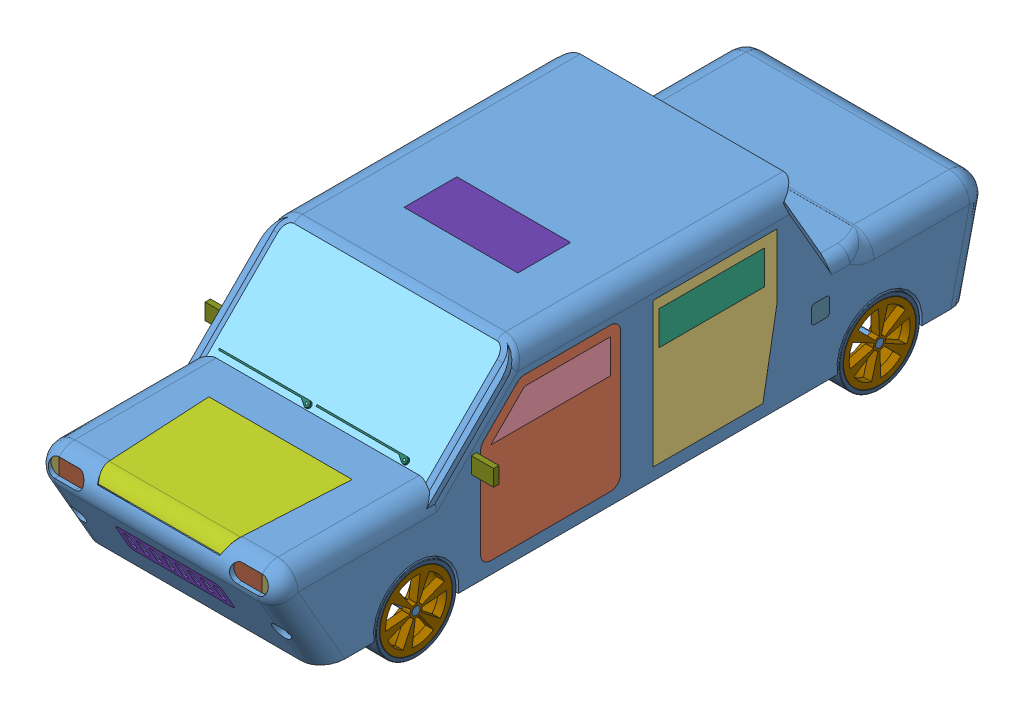
SolidWorks assembly Car Assembly, configuration Default. Lengths in mm.
Overall size (710 598.98 1752.8).
32 component instances, 17 part files, 91 mates.
Components (placement in the parent):
- Car Body-1: Car Body [Default] at origin size (608.06 474.25 1752.8)
- Car Door-4: Car Door [Default] at (-297 0 0) x (0 0 -1) z (1 0 0) size (344.71 355 3)
- Car Door-5: Car Door [Default] at (300 0 0) x (0 0 -1) z (1 0 0) size (344.71 355 3)
- Back Door-1: Back Door [Default] at (300 0 0) x (0 0 -1) z (1 0 0) size (304.4 355 3)
- Back Door-2: Back Door [Default] at (-297 0 0) x (0 0 -1) z (1 0 0) size (304.4 355 3)
- Front Door Window-3: Front Door Window [Default] at (300 0 0) x (0 0 -1) z (1 0 0) size (294.71 83.19 3)
- Front Door Window-4: Front Door Window [Default] at (-297 0 0) x (0 0 -1) z (1 0 0) size (294.71 83.19 3)
- Windshield-1: Windshield [Default] at (0 -20.2625 -20.3999) x (1 0 0) z (0 0.707107 0.707107) size (540 276.32 9)
- Back Door Window-1: Back Door Window [Default] at (300 0 0) x (0 0 -1) z (1 0 0) size (259.4 83.19 3)
- Back Door Window-2: Back Door Window [Default] at (-297 0 0) x (0 0 -1) z (1 0 0) size (259.4 83.19 3)
- Hood-3: Hood [Default] at (0 0 101.0363) size (352.8 60.9 300)
- Grill-1: Grill [Default] x (1 0 0) z (0 -0.5 0.866025) size (260 80.83 3)
- Rim-2: Rim [Default] at (210 -65.3854 -451.6615) x (0 0.28359 0.958946) z (-1 0 0) size (178 178 90)
- TIre Rubber-2: TIre Rubber [Default] at (300 157.4707 -48.093) x (0 -0.660547 -0.750784) z (1 0 0) size (198 198 90)
- Rim-3: Rim [Default] at (210 -204.7414 -1451.8024) x (0 0.918717 0.394916) z (-1 0 0) size (178 178 90)
- TIre Rubber-3: TIre Rubber [Default] at (300 222.8939 -1267.9808) x (0 -0.918717 -0.394916) z (1 0 0) size (198 198 90)
- Rim-4: Rim [Default] at (-210 37.9993 -0.654) x (0 -0.162417 -0.986722) z (1 0 0) size (178 178 90)
- TIre Rubber-4: TIre Rubber [Default] at (-300 -37.6009 -459.9436) x (0 0.162417 0.986722) z (-1 0 0) size (198 198 90)
- Rim-5: Rim [Default] at (-210 197.2827 -1228.1952) x (0 -0.8201 -0.57222) z (1 0 0) size (178 178 90)
- TIre Rubber-5: TIre Rubber [Default] at (-300 -184.4493 -1494.5465) x (0 0.8201 0.57222) z (-1 0 0) size (198 198 90)
- Headlight-2: Headlight [Default] at (0 0 96.0363) size (70 40 25)
- Headlight-3: Headlight [Default] at (0 0 71.0363) x (-1 0 0) z (0 0 -1) size (70 40 25)
- Indicator-2: Indicator [Default] at (0 0 96.0363) size (20 40 25)
- Indicator-3: Indicator [Default] at (0 0 71.0363) x (-1 0 0) z (0 0 -1) size (20 40 25)
- Fog Light-2: Fog Light [Default] at (-16.163 -36.9046 1.0363) x (0.988432 -0.151667 0) z (0 0 1) size (40 40 25)
- Fog Light-3: Fog Light [Default] at (452.9059 257.7511 1.0363) x (0.51071 0.859753 0) z (0 0 1) size (40 40 25)
- Fuel Tank Lid-2: Fuel Tank Lid [Default] at (300 0 0) x (0 0 -1) z (1 0 0) size (45 45 3)
- Wiper-2: Wiper [Default] at (0 -20.3312 -20.3312) x (1 0 0) z (0 0.707107 0.707107) size (227.5 15 6)
- Wiper-3: Wiper [Default] at (-240 -20.3312 -20.3312) x (1 0 0) z (0 0.707107 0.707107) size (227.5 15 6)
- Driver Mirror-1: Driver Mirror [Default] at (300 0 0) x (0 0 -1) z (1 0 0) size (13 40 55)
- Driver Mirror-2: Driver Mirror [Default] at (-355 0 0) x (0 0 -1) z (1 0 0) size (13 40 55)
- Sun Roof-2: Sun Roof [Default] at (0 450 0) x (1 0 0) z (0 1 0) size (280 130 3)
Mates (geometry in assembly coordinates):
- Coincident17: coincident aligned: line of Car Body-1 through (-300 276.8092 -391.4665) axis (0 -1 0); line of Car Door-4 through (-300 276.8092 -391.4665) axis (0 -1 0)
- Coincident18: coincident anti-aligned: plane of Car Body-1 through (-290 385 -711.1767) normal (0 -1 0); plane of Car Door-4 through (-300 385 -711.1767) normal (0 1 0)
- LimitAngle1: limit planar angle = 0 rad aligned: line of Car Door-4 through (-300 385 -711.1767) axis (0 0 1); line of Car Body-1 through (-300 385 -711.1767) axis (0 0 1)
- Coincident20: coincident aligned: line of Car Body-1 through (300 276.8092 -391.4665) axis (0 -1 0); line of Car Door-5 through (300 276.8092 -391.4665) axis (0 -1 0)
- Coincident21: coincident anti-aligned: plane of Car Body-1 through (290 385 -711.1767) normal (0 -1 0); plane of Car Door-5 through (297 385 -711.1767) normal (0 1 0)
- LimitAngle2: limit planar angle = 0 rad aligned: line of Car Door-5 through (300 385 -711.1767) axis (0 0 1); line of Car Body-1 through (300 385 -711.1767) axis (0 0 1)
- InPlace4: in place: plane of Car Body-1 through (300 0 0) normal (1 0 0); plane of ? through (300 0 0) normal (1 0 0); moOrthogonalPlaneRef_w of Car Body-1 through (300 0 0) normal (1 0 0); plane of ? through (300 0 0) normal (0 1 0); plane of Car Body-1 through (300 0 0) normal (1 0 0); plane of ? through (300 0 0) normal (0 0 -1); plane of Car Body-1 through (300 0 0) normal (1 0 0); unknown of ?
- Coincident23: coincident aligned: plane of Car Body-1; plane of Back Door-1
- Coincident24: coincident aligned: moOrthogonalPlaneRef_w of Car Body-1 through (300 0 0) normal (0 1 0); plane of Part8^Car Assembly-1 through (300 0 0) normal (0 1 0)
- Coincident25: coincident anti-aligned: moOrthogonalPlaneRef_w of Car Body-1 through (300 0 0) normal (0 0 1); plane of Part8^Car Assembly-1 through (300 0 0) normal (0 0 -1)
- Coincident26: coincident anti-aligned: plane of Car Body-1 through (-290 385 -816.1767) normal (0 0 -1); plane of Back Door-2 through (-300 385 -816.1767) normal (0 0 1)
- Coincident27: coincident anti-aligned: plane of Car Body-1 through (-290 30 -816.1767) normal (0 1 0); plane of Back Door-2 through (-300 30 -816.1767) normal (0 -1 0)
- Coincident28: coincident aligned: plane of Car Body-1 through (-300 0 0) normal (-1 0 0); plane of Back Door-2 through (-300 0 0) normal (-1 0 0)
- InPlace5: in place: plane of ? through (300 55 -711.1767) normal (1 0 0); plane of ? through (300 0 0) normal (1 0 0); plane of ? through (300 55 -711.1767) normal (1 0 0); plane of ? through (300 0 0) normal (0 1 0); plane of ? through (300 55 -711.1767) normal (1 0 0); plane of ? through (300 0 0) normal (0 0 -1); plane of ? through (300 55 -711.1767) normal (1 0 0); unknown of ?
- Coincident29: coincident aligned: plane of Car Door-5; plane of Front Door Window-3
- Coincident30: coincident aligned: moOrthogonalPlaneRef_w of Car Door-5 through (300 0 0) normal (0 1 0); plane of Part9^Car Assembly-1 through (300 0 0) normal (0 1 0)
- Coincident31: coincident anti-aligned: moOrthogonalPlaneRef_w of Car Door-5 through (300 0 0) normal (0 0 1); plane of Part9^Car Assembly-1 through (300 0 0) normal (0 0 -1)
- Coincident32: coincident anti-aligned: plane of Car Door-4 through (-300 276.8092 -416.4665) normal (0 -0.707107 -0.707107); plane of Front Door Window-4 through (-300 360 -499.6574) normal (0 0.707107 0.707107)
- Coincident33: coincident anti-aligned: plane of Car Door-4 through (-300 276.8092 -711.1767) normal (0 1 0); plane of Front Door Window-4 through (-300 276.8092 -416.4665) normal (0 -1 0)
- Coincident34: coincident aligned: plane of Car Door-4 through (-300 55 -711.1767) normal (-1 0 0); plane of Front Door Window-4 through (-300 0 0) normal (-1 0 0)
- InPlace8: in place: plane of ? through (300 0 0) normal (1 0 0); plane of ? through (300 0 0) normal (1 0 0); plane of ? through (300 0 0) normal (1 0 0); plane of ? through (300 0 0) normal (0 1 0); plane of ? through (300 0 0) normal (1 0 0); plane of ? through (300 0 0) normal (0 0 -1); plane of ? through (300 0 0) normal (1 0 0); unknown of ?
- Coincident41: coincident aligned: plane of Back Door-1; plane of Back Door Window-1
- Coincident42: coincident aligned: moOrthogonalPlaneRef_w of Back Door-1 through (300 0 0) normal (0 1 0); plane of Part12^Car Assembly-1 through (300 0 0) normal (0 1 0)
- Coincident43: coincident anti-aligned: moOrthogonalPlaneRef_w of Back Door-1 through (300 0 0) normal (0 0 1); plane of Part12^Car Assembly-1 through (300 0 0) normal (0 0 -1)
- Coincident44: coincident anti-aligned: plane of Back Door-2 through (-300 276.8092 -831.1767) normal (0 0 -1); plane of Back Door Window-2 through (-300 360 -831.1767) normal (0 0 1)
- Coincident45: coincident anti-aligned: plane of Back Door-2 through (-300 360 -831.1767) normal (0 -1 0); plane of Back Door Window-2 through (-300 360 -1090.5748) normal (0 1 0)
- Coincident46: coincident aligned: plane of Back Door-2 through (-300 0 0) normal (-1 0 0); plane of Back Door Window-2 through (-300 0 0) normal (-1 0 0)
- Coincident57: coincident aligned: line of Car Body-1 through (176.3977 250 -198.9637) axis (-1 0 0); line of Hood-3 through (176.3977 250 -198.9637) axis (-1 0 0)
- Coincident58: coincident: point of Car Body-1; point of Hood-3
- LimitAngle4: limit planar angle = 0 rad aligned: plane of Hood-3 through (0 250 101.0363) normal (0 1 0); plane of Car Body-1 through (300 250 -290.6624) normal (0 1 0)
- InPlace11: in place: plane of Grill-1 through (0 0 0) normal (0 -0.5 0.866025); plane of Grill-1 through (0 0 0) normal (0 0.866025 0.5); plane of Grill-1 through (0 0 0) normal (1 0 0); unknown of Grill-1
- Coincident60: coincident aligned: 
- Coincident61: coincident aligned: plane of Part15^Car Assembly-1 through (0 0 0) normal (0 0.866025 0.5)
- Coincident62: coincident anti-aligned: plane of Part15^Car Assembly-1 through (0 0 0) normal (1 0 0)
- Concentric1: concentric anti-aligned: cylinder of Car Body-1 through (300 15 -232.735) axis (-1 0 0) radius 10; cylinder of Rim-2 through (210 15 -232.735) axis (1 0 0) radius 10
- Coincident69: coincident aligned: plane of Car Body-1 through (300 0 0) normal (1 0 0); plane of Rim-2 through (300 15 -232.735) normal (1 0 0)
- Concentric2: concentric anti-aligned: cylinder of Rim-2 through (300 15 -232.735) axis (-1 0 0) radius 89; cylinder of TIre Rubber-2 through (210 15 -232.735) axis (1 0 0) radius 89
- Coincident70: coincident aligned: plane of Rim-2 through (300 15 -232.735) normal (1 0 0); plane of TIre Rubber-2 through (300 15 -232.735) normal (1 0 0)
- Lock1: lock: unknown of Rim-2; unknown of TIre Rubber-2
- Concentric3: concentric anti-aligned: cylinder of Car Body-1 through (300 15 -1373.6723) axis (-1 0 0) radius 10; cylinder of Rim-3 through (210 15 -1373.6723) axis (1 0 0) radius 10
- Coincident72: coincident aligned: plane of Car Body-1 through (300 15 -1373.6723) normal (1 0 0); plane of Rim-3 through (300 15 -1373.6723) normal (1 0 0)
- Concentric4: concentric anti-aligned: cylinder of Rim-3 through (300 15 -1373.6723) axis (-1 0 0) radius 89; cylinder of TIre Rubber-3 through (210 15 -1373.6723) axis (1 0 0) radius 89
- Coincident73: coincident aligned: plane of Rim-3 through (300 15 -1373.6723) normal (1 0 0); plane of TIre Rubber-3 through (300 15 -1373.6723) normal (1 0 0)
- Lock2: lock: unknown of Rim-3; unknown of TIre Rubber-3
- Concentric5: concentric anti-aligned: cylinder of Car Body-1 through (-300 15 -232.735) axis (1 0 0) radius 10; cylinder of Rim-4 through (-210 15 -232.735) axis (-1 0 0) radius 10
- Coincident74: coincident aligned: plane of Car Body-1 through (-300 0 0) normal (-1 0 0); plane of Rim-4 through (-300 15 -232.735) normal (-1 0 0)
- Concentric6: concentric anti-aligned: cylinder of Rim-4 through (-300 15 -232.735) axis (1 0 0) radius 89; cylinder of TIre Rubber-4 through (-210 15 -232.735) axis (-1 0 0) radius 89
- Coincident75: coincident aligned: plane of Rim-4 through (-300 15 -232.735) normal (-1 0 0); plane of TIre Rubber-4 through (-300 15 -232.735) normal (-1 0 0)
- Lock3: lock: unknown of Rim-4; unknown of TIre Rubber-4
- Concentric7: concentric anti-aligned: cylinder of Car Body-1 through (-300 15 -1373.6723) axis (1 0 0) radius 10; cylinder of Rim-5 through (-210 15 -1373.6723) axis (-1 0 0) radius 10
- Coincident77: coincident aligned: plane of Car Body-1 through (-300 0 0) normal (-1 0 0); plane of Rim-5 through (-300 15 -1373.6723) normal (-1 0 0)
- Concentric8: concentric anti-aligned: cylinder of Rim-5 through (-300 15 -1373.6723) axis (1 0 0) radius 89; cylinder of TIre Rubber-5 through (-210 15 -1373.6723) axis (-1 0 0) radius 89
- Coincident78: coincident aligned: plane of Rim-5 through (-300 15 -1373.6723) normal (-1 0 0); plane of TIre Rubber-5 through (-300 15 -1373.6723) normal (-1 0 0)
- Lock4: lock: unknown of Rim-5; unknown of TIre Rubber-5
- Concentric9: concentric aligned: cylinder of Car Body-1 through (-200 212.5 71.0363) axis (0 0 1) radius 20; cylinder of Headlight-2 through (-200 212.5 71.0363) axis (0 0 1) radius 20
- Coincident82: coincident anti-aligned: plane of Car Body-1 through (-250 212.5 71.0363) normal (0 0 1); plane of Headlight-2 through (-200 212.5 71.0363) normal (0 0 -1)
- Concentric10: concentric anti-aligned: cylinder of Car Body-1 through (200 212.5 71.0363) axis (0 0 1) radius 20; cylinder of Headlight-3 through (200 212.5 96.0363) axis (0 0 -1) radius 20
- Coincident83: coincident anti-aligned: plane of Car Body-1 through (250 212.5 71.0363) normal (0 0 1); plane of Headlight-3 through (200 212.5 71.0363) normal (0 0 -1)
- Coincident84: coincident anti-aligned: plane of Car Body-1 through (250 232.5 71.0363) normal (0 -1 0); plane of Headlight-3 through (200 232.5 96.0363) normal (0 1 0)
- Coincident85: coincident anti-aligned: plane of Car Body-1 through (-250 232.5 71.0363) normal (0 -1 0); plane of Headlight-2 through (-200 232.5 71.0363) normal (0 1 0)
- Concentric11: concentric aligned: cylinder of Car Body-1 through (-250 212.5 71.0363) axis (0 0 1) radius 20; cylinder of Indicator-2 through (-250 212.5 71.0363) axis (0 0 1) radius 20
- Coincident90: coincident anti-aligned: plane of Headlight-2 through (-250 232.5 71.0363) normal (-1 0 0); plane of Indicator-2 through (-250 232.5 71.0363) normal (1 0 0)
- Coincident91: coincident anti-aligned: plane of Car Body-1 through (-250 212.5 71.0363) normal (0 0 1); plane of Indicator-2 through (-250 212.5 71.0363) normal (0 0 -1)
- Concentric12: concentric anti-aligned: cylinder of Car Body-1 through (250 212.5 71.0363) axis (0 0 1) radius 20; cylinder of Indicator-3 through (250 212.5 96.0363) axis (0 0 -1) radius 20
- Coincident92: coincident anti-aligned: plane of Headlight-3 through (250 232.5 96.0363) normal (1 0 0); plane of Indicator-3 through (250 232.5 96.0363) normal (-1 0 0)
- Coincident93: coincident anti-aligned: plane of Car Body-1 through (250 212.5 71.0363) normal (0 0 1); plane of Indicator-3 through (250 212.5 71.0363) normal (0 0 -1)
- Concentric13: concentric anti-aligned: cylinder of Car Body-1 through (-250 87.5 1.0363) axis (0 0 1) radius 20; cylinder of Fog Light-2 through (-250 87.5 26.0363) axis (0 0 -1) radius 20
- Coincident100: coincident anti-aligned: plane of Car Body-1 through (-250 87.5 1.0363) normal (0 0 1); plane of Fog Light-2 through (-250 87.5 1.0363) normal (0 0 -1)
- Concentric14: concentric anti-aligned: cylinder of Car Body-1 through (250 87.5 1.0363) axis (0 0 1) radius 20; cylinder of Fog Light-3 through (250 87.5 26.0363) axis (0 0 -1) radius 20
- Coincident101: coincident anti-aligned: plane of Car Body-1 through (250 87.5 1.0363) normal (0 0 1); plane of Fog Light-3 through (250 87.5 1.0363) normal (0 0 -1)
- Coincident105: coincident aligned: line of Car Body-1 through (300 172 -1205.5748) axis (0 -1 0); line of Fuel Tank Lid-2 through (300 172 -1205.5748) axis (0 -1 0)
- Coincident106: coincident anti-aligned: plane of Car Body-1 through (290 180 -1213.5748) normal (0 -1 0); plane of Fuel Tank Lid-2 through (297 180 -1242.5748) normal (0 1 0)
- LimitAngle5: limit planar angle = 0 rad aligned: line of Fuel Tank Lid-2 through (300 180 -1242.5748) axis (0 0 1); line of Car Body-1 through (300 180 -1242.5748) axis (0 0 1)
- Concentric15: concentric aligned: cylinder of Windshield-1 through (210 261.3137 -293.4909) axis (0 -0.707107 -0.707107) radius 3; cylinder of Wiper-2 through (210 261.3137 -293.4909) axis (0 -0.707107 -0.707107) radius 3
- Coincident111: coincident aligned: plane of Windshield-1 through (210 261.3137 -293.4909) normal (0 0.707107 0.707107); plane of Wiper-2 through (210 261.3137 -293.4909) normal (0 0.707107 0.707107)
- LimitAngle6: limit planar angle = 0 rad aligned: line of Wiper-2 through (-10 264.1421 -296.3193) axis (1 0 0); line of Windshield-1 through (-250 250 -290.6624) axis (1 0 0)
- Coincident113: coincident anti-aligned: plane of Car Body-1 through (270 238.7547 -293.5593) normal (-1 0 0); plane of Windshield-1 through (270 243.7044 -288.6095) normal (1 0 0)
- Coincident114: coincident anti-aligned: plane of Car Body-1 through (250 434.1421 -488.9467) normal (0 -0.707107 0.707107); plane of Windshield-1 through (250 439.0919 -483.997) normal (0 0.707107 -0.707107)
- Concentric16: concentric aligned: cylinder of Windshield-1 through (-30 261.3137 -293.4909) axis (0 -0.707107 -0.707107) radius 3; cylinder of Wiper-3 through (-30 261.3137 -293.4909) axis (0 -0.707107 -0.707107) radius 3
- Coincident115: coincident aligned: plane of Windshield-1 through (-30 261.3137 -293.4909) normal (0 0.707107 0.707107); plane of Wiper-3 through (-30 261.3137 -293.4909) normal (0 0.707107 0.707107)
- LimitAngle7: limit planar angle = 0 rad aligned: line of Wiper-3 through (-250 264.1421 -296.3193) axis (1 0 0); line of Windshield-1 through (-250 250 -290.6624) axis (1 0 0)
- Coincident118: coincident anti-aligned: plane of Car Body-1 through (250 434.1421 -488.9467) normal (0 -0.707107 0.707107); plane of Windshield-1 through (250 439.0919 -483.997) normal (0 0.707107 -0.707107)
- Coincident119: coincident anti-aligned: plane of Car Body-1 through (270 238.7547 -293.5593) normal (-1 0 0); plane of Windshield-1 through (270 243.7044 -288.6095) normal (1 0 0)
- Coincident120: coincident anti-aligned: line of Car Body-1 through (250 250 -290.6624) axis (-1 0 0); line of Windshield-1 through (-250 250 -290.6624) axis (1 0 0)
- InPlace18: in place: plane of Car Body-1 through (300 0 0) normal (1 0 0); plane of ? through (300 0 0) normal (1 0 0); plane of Car Body-1 through (300 0 0) normal (1 0 0); plane of ? through (300 0 0) normal (0 1 0); plane of Car Body-1 through (300 0 0) normal (1 0 0); plane of ? through (300 0 0) normal (0 0 -1); plane of Car Body-1 through (300 0 0) normal (1 0 0); unknown of ?
- Coincident121: coincident aligned: plane of Car Body-1; plane of Driver Mirror-1
- Coincident122: coincident aligned: moOrthogonalPlaneRef_w of Car Body-1 through (300 0 0) normal (0 1 0); plane of Part7^Car Assembly-1 through (300 0 0) normal (0 1 0)
- Coincident123: coincident anti-aligned: moOrthogonalPlaneRef_w of Car Body-1 through (300 0 0) normal (0 0 1); plane of Part7^Car Assembly-1 through (300 0 0) normal (0 0 -1)
- Coincident121: coincident aligned: line of Car Body-1 through (-140 450 -643.0888) axis (1 0 0); line of Sun Roof-2 through (-140 450 -643.0888) axis (1 0 0)
- Coincident122: coincident anti-aligned: plane of Car Body-1 through (-140 440 -773.0888) normal (1 0 0); plane of Sun Roof-2 through (-140 447 -773.0888) normal (-1 0 0)
- LimitAngle8: limit planar angle = 0 rad aligned: line of Sun Roof-2 through (140 450 -643.0888) axis (0 0 -1); line of Car Body-1 through (140 450 -643.0888) axis (0 0 -1)
